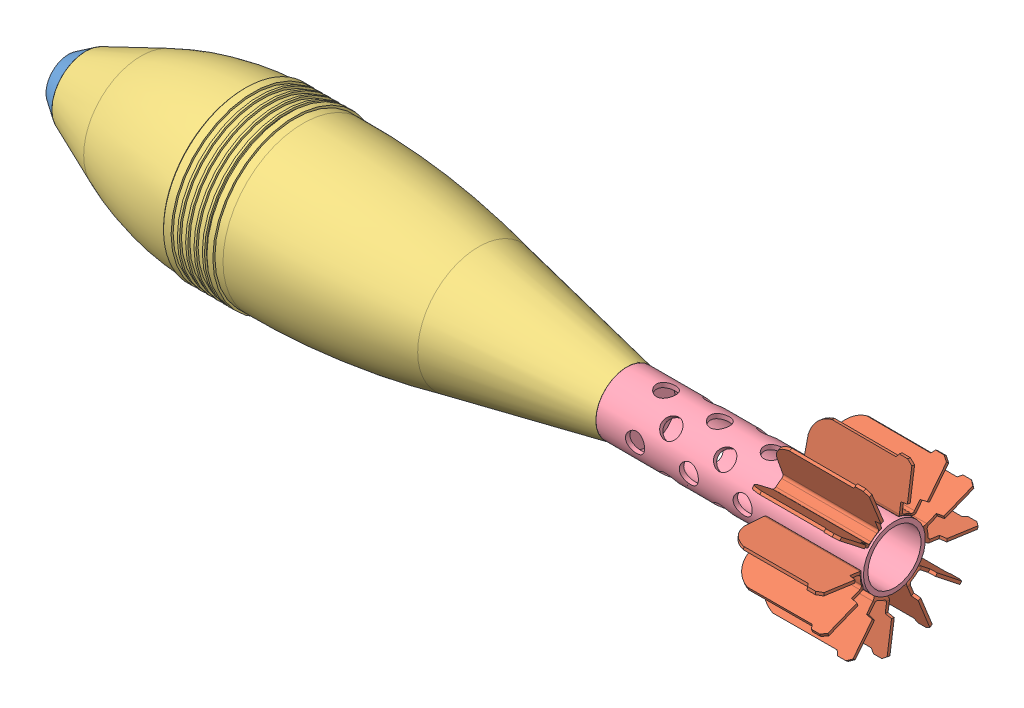
SolidWorks assembly Sklop projektila 120mm, configuration Default. Lengths in mm.
Overall size (611.14 133.24 133.24).
10 component instances, 5 part files, 9 mates.
Components (placement in the parent):
- adapter-1: adapter [Default] at (0.1651 29.5999 45.4678) size (28.72 49.78 49.78)
- krilce-1: krilce [Default] at (521.8251 50.5307 36.5281) x (1 0 0) z (0 0.39278 0.919633) size (75.35 35.57 30.85)
- tijelo projektila-1: tijelo projektila [Default] at (197.1501 29.5999 45.4678) size (397.29 120.54 120.54)
- tijelo stabilizatora-1: tijelo stabilizatora [Default] at (485.5951 29.5999 45.4678) size (213.24 45.52 45.52)
- krilce-2: krilce [Default] at (521.8251 47.8073 59.1246) x (1 0 0) z (0 -0.600035 0.799974) size (75.35 35.57 30.85)
- krilce-3: krilce [Default] at (521.8251 26.8765 68.0643) x (1 0 0) z (0 -0.992815 -0.119659) size (75.35 35.57 30.85)
- krilce-4: krilce [Default] at (521.8251 8.6691 54.4074) x (1 0 0) z (0 -0.39278 -0.919633) size (75.35 35.57 30.85)
- krilce-5: krilce [Default] at (521.8251 11.3925 31.811) x (1 0 0) z (0 0.600035 -0.799974) size (75.35 35.57 30.85)
- krilce-6: krilce [Default] at (521.8251 32.3233 22.8713) x (1 0 0) z (0 0.992815 0.119659) size (75.35 35.57 30.85)
- eksploziv-2: eksploziv [Default] at (197.1501 29.5999 45.4678) x (1 0 0) z (0 0.804248 -0.594294) size (354.55 95.27 95.27)
Mates (geometry in assembly coordinates):
- Coincident2: coincident aligned: axis of adapter-1 through (14.5251 29.5999 45.4678) axis (-1 0 0); axis of tijelo projektila-1 through (14.5051 29.5999 45.4678) axis (-1 0 0)
- Coincident4: coincident aligned: axis of tijelo projektila-1 through (395.7951 29.5999 45.4678) axis (-1 0 0); axis of tijelo stabilizatora-1 through (395.7951 29.5999 45.4678) axis (-1 0 0)
- Coincident5: coincident anti-aligned: plane of tijelo projektila-1 through (395.7951 52.4399 45.4678) normal (1 0 0); plane of tijelo stabilizatora-1 through (395.7951 46.0999 45.4678) normal (-1 0 0)
- Coincident6: coincident anti-aligned: plane of adapter-1 through (-1.4949 54.4899 45.4678) normal (1 0 0); plane of tijelo projektila-1 through (-1.4949 54.4899 45.4678) normal (-1 0 0)
- Concentric1: concentric aligned: cylinder of krilce-1 through (500.6803 29.5999 45.4678) axis (-1 0 0) radius 22.76; cylinder of tijelo stabilizatora-1 through (378.9751 29.5999 45.4678) axis (-1 0 0) radius 22.76
- Tangent1: tangent: torus of krilce-1; plane of tijelo stabilizatora-1 through (592.2151 52.3599 45.4678) normal (1 0 0)
- Coincident8: coincident: axis of tijelo projektila-1 through (149.7147 29.5999 45.4678) axis (-1 0 0); axis of eksploziv-2 through (-174.4843 29.5999 45.4678) axis (1 0 0)
- Concentric2: concentric: cylinder of tijelo projektila-1 through (-1.4949 29.5999 45.4678) axis (-1 0 0) radius 47.63; cylinder of eksploziv-2 through (-92.2843 29.5999 45.4678) axis (1 0 0) radius 47.63
- Coincident9: coincident aligned: cone of tijelo projektila-1 through (286.8551 29.5999 45.4678) axis (1 0 0); cone of eksploziv-2 through (361.388 29.5999 45.4678) axis (1 0 0)
